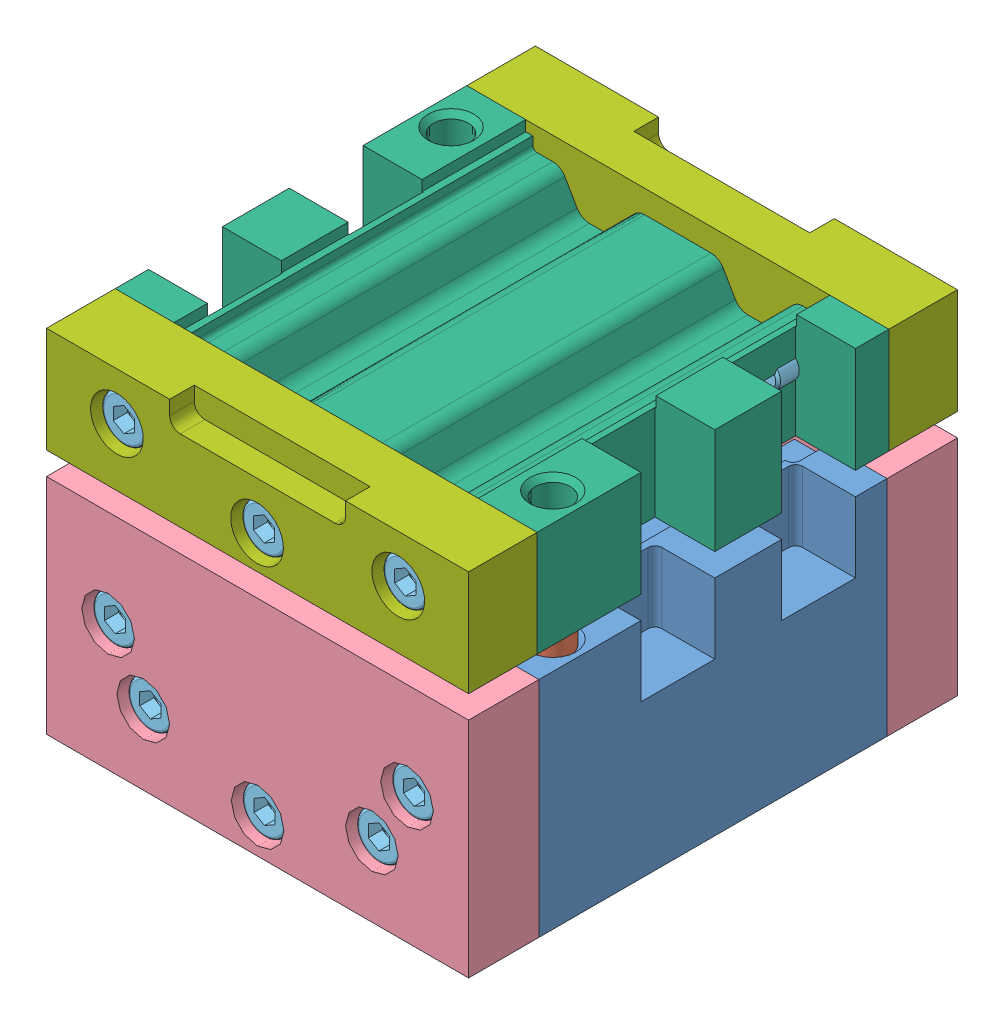
SolidWorks assembly Сборка, configuration По умолчанию. Lengths in mm.
Overall size (120 100 139).
28 component instances, 7 part files, 5 mates.
Components (placement in the parent):
- сборка нижней пресс формы-1: сборка нижней пресс формы [По умолчанию] at origin size (120 88.5 139)
  - Матрица пресс-формы трак-1: Матрица пресс-формы трак [По умолчанию] at (94.4955 113.7729 76.599) x (-1 0 0) z (0 -1 0) size (120 99 63.5)
  - Направляющая-1: Направляющая [По умолчанию] at (134.3195 83.7729 119.5159) x (0 1 0) z (-0.942376 0 0.334555) size (55 10 10)
  - Направляющая-2: Направляющая [По умолчанию] at (30.3195 83.7729 44.5159) x (0 1 0) z (-0.954844 0 0.297108) size (55 10 10)
  - Подстановка-1: Подстановка [По умолчанию] at (85.2823 100.5229 55.4864) x (0 1 0) z (-0.987622 0 -0.156852) size (36.5 12 12)
  - Подстановка-2: Подстановка [По умолчанию] at (83.6486 100.5229 111.7054) x (0 1 0) z (-0.443057 0 -0.896493) size (36.5 12 12)
  - Боковина пресс-формы-1: Боковина пресс-формы [По умолчанию] at (82.3195 82.0229 131.5159) x (1 0 0) z (0 -1 0) size (120 20 63.5)
  - Боковина пресс-формы-2: Боковина пресс-формы [По умолчанию] at (82.3195 82.0229 32.5159) x (-1 0 0) z (0 -1 0) size (120 20 63.5)
  - болтец-1: болтец [EN ISO 4762 M8 x 25 - 25S] at (114.8195 70.2729 149.5159) x (0 0 -1) z (1 0 0) size (33 13 13)
  - болтец-2: болтец [EN ISO 4762 M8 x 25 - 25S] at (82.3195 60.2729 149.5159) x (0 0 -1) z (1 0 0) size (33 13 13)
  - болтец-3: болтец [EN ISO 4762 M8 x 25 - 25S] at (49.8195 70.2729 149.5159) x (0 0 -1) z (1 0 0) size (33 13 13)
  - болтец-4: болтец [EN ISO 4762 M8 x 25 - 25N] at (124.8195 86.2729 149.5159) x (0 0 -1) z (1 0 0) size (33 13 13)
  - болтец-5: болтец [EN ISO 4762 M8 x 25 - 25N] at (39.8195 86.2729 149.5159) x (0 0 -1) z (1 0 0) size (33 13 13)
  - болтец-6: болтец [EN ISO 4762 M8 x 25 - 25N] at (39.8195 86.2729 14.5159) x (0 0 1) z (-1 0 0) size (33 13 13)
  - болтец-7: болтец [EN ISO 4762 M8 x 25 - 25N] at (49.8195 70.2729 14.5159) x (0 0 1) z (-1 0 0) size (33 13 13)
  - болтец-8: болтец [EN ISO 4762 M8 x 25 - 25N] at (82.3195 60.2729 14.5159) x (0 0 1) z (-1 0 0) size (33 13 13)
  - болтец-9: болтец [EN ISO 4762 M8 x 25 - 25N] at (114.8195 70.2729 14.5159) x (0 0 1) z (-1 0 0) size (33 13 13)
  - болтец-10: болтец [EN ISO 4762 M8 x 25 - 25N] at (124.8195 86.2729 14.5159) x (0 0 1) z (-1 0 0) size (33 13 13)
- сборка верхней пресс формы-1: сборка верхней пресс формы [По умолчанию] at origin size (120 30 139)
  - Пуансон (на бис, дымись канабис)-1: Пуансон (на бис, дымись канабис) [По умолчанию] at (69.8379 150.2729 72.2482) x (-1 0 0) z (0 0 1) size (120 30 100)
  - Боковина пуансона-1: Боковина пуансона [По умолчанию] at (82.3195 135.2729 132.0159) x (1 0 0) z (0 -1 0) size (120 19.5 30)
  - Боковина пуансона-2: Боковина пуансона [По умолчанию] at (82.3195 135.2729 32.0159) x (-1 0 0) z (0 -1 0) size (120 19.5 30)
  - болтец-1: болтец [EN ISO 4762 M8 x 25 - 25N] at (122.3195 136.7729 149.5159) x (0 0 -1) z (1 0 0) size (33 13 13)
  - болтец-2: болтец [EN ISO 4762 M8 x 25 - 25N] at (82.18 129.7729 149.5159) x (0 0 -1) z (1 0 0) size (33 13 13)
  - болтец-3: болтец [EN ISO 4762 M8 x 25 - 25N] at (42.3195 136.7729 149.5159) x (0 0 -1) z (1 0 0) size (33 13 13)
  - болтец-4: болтец [EN ISO 4762 M8 x 25 - 25N] at (42.3195 136.7729 14.5159) x (0 0 1) z (-1 0 0) size (33 13 13)
  - болтец-5: болтец [EN ISO 4762 M8 x 25 - 25N] at (82.4589 129.7729 14.5159) x (0 0 1) z (-1 0 0) size (33 13 13)
  - болтец-6: болтец [EN ISO 4762 M8 x 25 - 25N] at (122.3195 136.7729 14.5159) x (0 0 1) z (-1 0 0) size (33 13 13)
Mates (geometry in assembly coordinates):
- Совпадение38: coincident aligned: plane of сборка нижней пресс формы-1/Матрица пресс-формы трак-1 through (142.3195 50.2729 32.5159) normal (1 0 0); plane of Сборка2^Сборка-1/Пуансон (на бис, дымись канабис)-1 through (142.3195 120.2729 32.0159) normal (1 0 0)
- Параллельность4: parallel aligned: cylinder of сборка нижней пресс формы-1/Направляющая-1 through (134.3195 83.7729 119.5159) axis (0 -1 0) radius 5; cylinder of Сборка2^Сборка-1/Пуансон (на бис, дымись канабис)-1 through (134.2575 220.2729 119.5159) axis (0 -1 0) radius 5
- Концентричный38: concentric aligned: cylinder of сборка нижней пресс формы-1/Направляющая-2 through (30.3195 83.7729 44.5159) axis (0 -1 0) radius 5; cylinder of Сборка2^Сборка-1/Пуансон (на бис, дымись канабис)-1 through (30.3195 220.2729 44.5159) axis (0 -1 0) radius 5
- Концентричный39: concentric aligned: cylinder of сборка нижней пресс формы-1/Направляющая-2 through (30.3195 83.7729 44.5159) axis (0 -1 0) radius 5; cylinder of Сборка2^Сборка-1/Пуансон (на бис, дымись канабис)-1 through (30.3195 220.2729 44.5159) axis (0 -1 0) radius 5
- Совпадение39: coincident anti-aligned: circle of сборка нижней пресс формы-1/Подстановка-1; plane of Сборка2^Сборка-1/Пуансон (на бис, дымись канабис)-1 through (69.8379 120.2729 72.2482) normal (0 -1 0)
